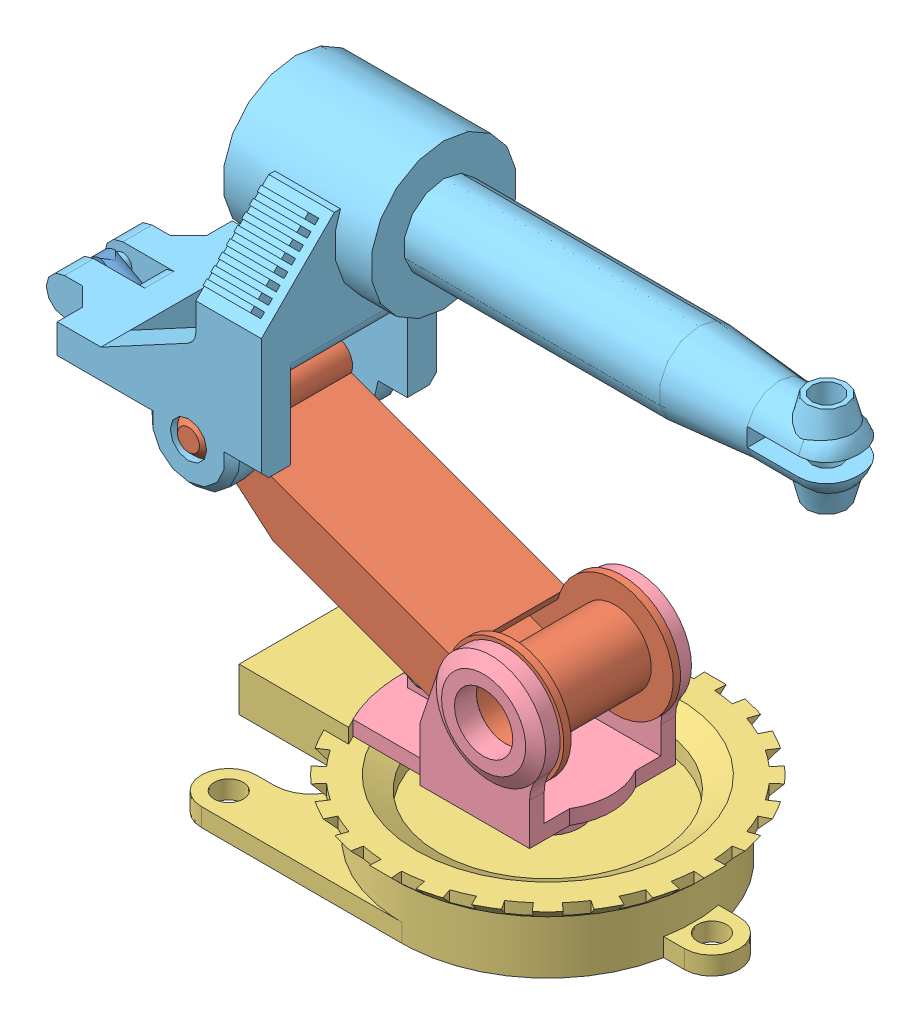
SolidWorks assembly notreal, configuration Default. Lengths in mm.
Overall size (195.82 140.34 92).
6 component instances, 6 part files, 15 mates.
Components (placement in the parent):
- ActPiston-1: ActPiston [Default] at (-68.029 50.2402 0) x (0 0 1) z (-0.484661 -0.874702 0) size (8 84.03 8)
- MainArm-1: MainArm [Default] at (4.3934 45.6066 16) x (-0.34202 -0.939693 0) z (0.939693 -0.34202 0) size (32 48 105)
- PlateBase(New Design)-1: PlateBase(New Design) [Default] at origin size (117.14 24 92)
- Rotating Base-1: Rotating Base [Default] at (0 20 0) size (59.39 48.61 44)
- SubArm-2: SubArm [Default] at (-74.5408 74.3363 24) x (1 0 0) z (0 -1 0) size (195.38 60.51 78)
- ActHousing-1: ActHousing [Default] at (-36.7482 32.908 0) x (0 0 1) z (-0.484661 -0.874702 0) size (10 60.02 10)
Mates (geometry in assembly coordinates):
- Concentric1: concentric aligned: cylinder of PlateBase(New Design)-1 through (0 12 0) axis (0 1 0) radius 6; cylinder of Rotating Base-1 through (0 12 0) axis (0 1 0) radius 6
- Coincident1: coincident anti-aligned: plane of PlateBase(New Design)-1 through (0 12 0) normal (0 1 0); plane of Rotating Base-1 through (0 12 0) normal (0 -1 0)
- Coincident3: coordinate: point of PlateBase(New Design)-1
- Concentric2: concentric aligned: cylinder of MainArm-1 through (4.3934 45.6066 -16) axis (0 0 1) radius 8; cylinder of Rotating Base-1 through (4.3934 45.6066 -73.2147) axis (0 0 1) radius 8
- Coincident4: coincident anti-aligned: plane of MainArm-1 through (4.3934 45.6066 -16) normal (0 0 -1); plane of Rotating Base-1 through (19.3934 62.7339 -16) normal (0 0 1)
- Concentric3: concentric aligned: cylinder of MainArm-1 through (-74.5408 74.3363 -24) axis (0 0 1) radius 5; cylinder of SubArm-1 through (-74.5408 74.3363 -24) axis (0 0 1) radius 5
- Coincident5: coincident anti-aligned: plane of MainArm-1 through (4.3934 45.6066 -16) normal (0 0 -1); plane of SubArm-2 through (-98.5408 57.4867 -16) normal (0 0 1)
- Concentric4: concentric aligned: cylinder of ActPiston-1 through (-120.5408 79.3363 -2) axis (0 0 1) radius 2.5; cylinder of SubArm-1 through (-120.5408 79.3363 -11.0711) axis (0 0 1) radius 2.5
- Width1: width anti-aligned: plane of SubArm-2 through (-110.5408 101.3363 4) normal (0 0 -1); plane of ActPiston-1 through (-110.5408 101.3363 -4) normal (0 0 1); plane of SubArm-2 through (-120.5408 79.3363 2) normal (0 0 1); plane of ActPiston-1 through (-120.5408 79.3363 -2) normal (0 0 -1)
- Concentric5: concentric aligned: cylinder of Rotating Base-1 through (-31.5 30 -7.5) axis (0 0 1) radius 2.5; cylinder of ActHousing-1 through (-31.5 30 -5) axis (0 0 1) radius 2.5
- Coincident6: coincident anti-aligned: plane of Rotating Base-1 through (-36 34 -2.5) normal (0 0 -1); plane of ActHousing-1 through (-30.0998 24.2738 -2.5) normal (0 0 1)
- Concentric7: concentric aligned: cylinder of ActPiston-1 through (-116.1376 76.8966 0) axis (0.874702 -0.484661 0) radius 4; cylinder of ActHousing-1 through (-83.9821 59.0796 0) axis (0.874702 -0.484661 0) radius 4
- Parallel1: parallel aligned: plane of PlateBase(New Design)-1 through (-64.641 12 20) normal (0 0 1); plane of Rotating Base-1 through (0 24 17.5) normal (0 0 1)
- Parallel2: parallel aligned: plane of PlateBase(New Design)-1 through (0 24 0) normal (0 1 0); plane of SubArm-2 through (-110.5408 84.3363 24) normal (0 1 0)
- Angle1: planar angle = 0.349066 rad anti-aligned: plane of MainArm-1 through (-7.6737 35.1002 -16) normal (-0.34202 -0.939693 0); plane of Rotating Base-1 through (19.3934 24 -16) normal (0 1 0)
